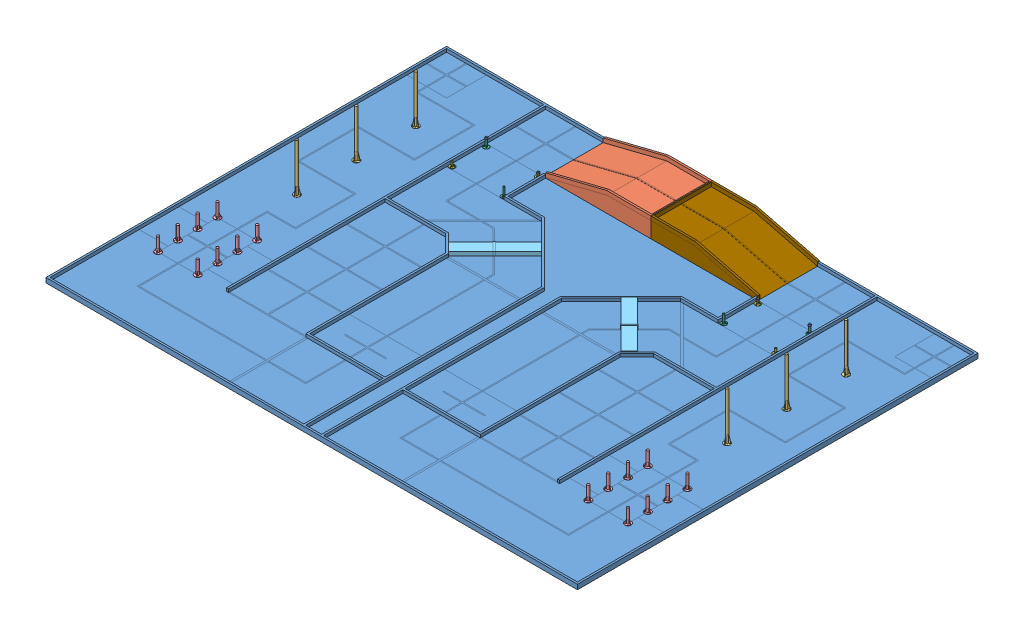
SolidWorks assembly Arena assmebly, configuration Default. Lengths in mm.
Overall size (13400 1240 10100).
39 component instances, 9 part files, 54 mates.
Components (placement in the parent):
- Layout-1: Layout [Default] at (7939.3308 4716.4188 7585.328) size (13400 120 10100)
- mountain-1: mountain [Default] at (7604.3187 4736.4188 3571.4942) size (2700.73 500 1550)
- forest tree-1: forest tree [Default] at (2179.3187 4741.4188 4846.4942) x (-0.822314 0 0.569035) z (-0.569035 0 -0.822314) size (160 1200 160)
- forest tree-2: forest tree [Default] at (2179.3187 4741.4188 6346.4942) size (160 1200 160)
- forest tree-3: forest tree [Default] at (2179.3187 4741.4188 7846.4942) size (160 1200 160)
- bridge-1: bridge [Default] at (1679.3187 4741.4188 9346.4942) size (160 350 160)
- bridge-2: bridge [Default] at (1679.3187 4741.4188 10846.4942) size (160 350 160)
- bridge-3: bridge [Default] at (1679.3187 4741.4188 10346.4942) size (160 350 160)
- bridge-4: bridge [Default] at (1679.3187 4741.4188 9846.4942) size (160 350 160)
- bridge-5: bridge [Default] at (2679.3187 4741.4188 9846.4942) size (160 350 160)
- bridge-6: bridge [Default] at (2679.3187 4741.4188 10846.4942) size (160 350 160)
- bridge-7: bridge [Default] at (2679.3187 4741.4188 10346.4942) size (160 350 160)
- bridge-8: bridge [Default] at (2679.3187 4741.4188 9346.4942) size (160 350 160)
- sand dune-1: sand dune [Default] at (5914.6178 4786.4188 6581.2976) x (0.707107 0 -0.707107) z (0.707107 0 0.707107) size (1661 103 306)
- big tussock-1: big tussock [Default] at (3524.3187 4741.4188 4416.4942) x (0.505909 0 -0.862587) z (0.862587 0 0.505909) size (140 220 140)
- big tussock-2: big tussock [Default] at (4834.3187 4741.4188 5276.4942) size (140 220 140)
- small tussock-1: small tussock [Default] at (4834.3187 4741.4188 4416.4942) size (140 120 140)
- small tussock-2: small tussock [Default] at (3524.3187 4741.4188 5276.4942) size (140 120 140)
- rope-2: rope [Default] at (4837.6429 4808.0977 4416.2239) x (0.973213 0.084542 0.213798) z (-0.212051 -0.029236 0.976821) size (71.08 49.96 70.15)
- rope-3: rope [Default] at (3527.7017 4909.2003 4416.5029) x (0.996381 0.084578 0.008439) z (-0.008428 -0.000496 0.999964) size (71.08 49.96 70.15)
- forest tree-7: forest tree [Default] at (13029.3187 4741.4188 4846.4942) x (-0.822314 0 -0.569035) z (0.569035 0 -0.822314) size (160 1200 160)
- forest tree-8: forest tree [Default] at (13029.3187 4741.4188 6346.4942) size (160 1200 160)
- forest tree-9: forest tree [Default] at (13029.3187 4741.4188 7846.4942) size (160 1200 160)
- sand dune-3: sand dune [Default] at (9294.0196 4786.4188 6581.2976) x (-0.707107 0 -0.707107) z (0.707107 0 -0.707107) size (1661 103 306)
- bridge-17: bridge [Default] at (12529.3187 4741.4188 10846.4942) x (-1 0 0) z (0 0 -1) size (160 350 160)
- bridge-18: bridge [Default] at (12529.3187 4741.4188 10346.4942) x (-1 0 0) z (0 0 -1) size (160 350 160)
- bridge-19: bridge [Default] at (12529.3187 4741.4188 9846.4942) x (-1 0 0) z (0 0 -1) size (160 350 160)
- bridge-20: bridge [Default] at (12529.3187 4741.4188 9346.4942) x (-1 0 0) z (0 0 -1) size (160 350 160)
- bridge-21: bridge [Default] at (13529.3187 4741.4188 9346.4942) x (-1 0 0) z (0 0 -1) size (160 350 160)
- bridge-22: bridge [Default] at (13529.3187 4741.4188 9846.4942) x (-1 0 0) z (0 0 -1) size (160 350 160)
- bridge-23: bridge [Default] at (13529.3187 4741.4188 10346.4942) x (-1 0 0) z (0 0 -1) size (160 350 160)
- bridge-24: bridge [Default] at (13529.3187 4741.4188 10846.4942) x (-1 0 0) z (0 0 -1) size (160 350 160)
- small tussock-5: small tussock [Default] at (11684.3187 4741.4188 5276.4942) size (140 120 140)
- rope-6: rope [Default] at (11680.9357 4909.2003 4416.5029) x (0.996381 -0.084578 -0.008439) z (0.008428 -0.000496 0.999964) size (71.08 49.96 70.15)
- small tussock-6: small tussock [Default] at (10374.3187 4741.4188 4416.4942) size (140 120 140)
- big tussock-5: big tussock [Default] at (10374.3187 4741.4188 5276.4942) size (140 220 140)
- big tussock-6: big tussock [Default] at (11684.3187 4741.4188 4416.4942) x (0.505909 0 0.862587) z (-0.862587 0 0.505909) size (140 220 140)
- rope-7: rope [Default] at (10370.9945 4808.0977 4416.2239) x (0.973213 -0.084542 -0.213798) z (0.212051 -0.029236 0.976821) size (71.08 49.96 70.15)
- mountain_blueside-1: mountain_blueside [Default] at (7604.3187 4736.4188 3571.4942) x (-1 0 0) z (0 0 -1) size (2700.73 500 1550)
Mates (geometry in assembly coordinates):
- Coincident3: coincident anti-aligned: plane of Layout-1 through (7939.3308 4736.4188 7585.328) normal (0 1 0); plane of mountain-1 through (4904.3187 4736.4188 2796.4942) normal (0 -1 0)
- Coincident6: coincident aligned: plane of Layout-1 through (7939.3308 4696.4188 2796.4942) normal (0 0 -1); plane of mountain-1 through (7604.3187 4736.4188 2796.4942) normal (0 0 -1)
- Coincident8: coincident anti-aligned: line of Layout-1 through (4904.3187 4736.4188 4346.4942) axis (0 0 -1); line of mountain-1 through (4904.3187 4736.4188 2796.4942) axis (0 0 1)
- Coincident9: coincident aligned: plane of Layout-1 through (7939.3308 4736.4188 7585.328) normal (0 1 0); circle of forest tree-1
- Distance1: distance = 1225 mm: cylinder of forest tree-1 through (2179.3187 4936.4188 4846.4942) axis (0 -1 0) radius 30; plane of Layout-1 through (954.3187 4696.4188 7585.328) normal (1 0 0)
- Distance2: distance = 2000 mm: cylinder of forest tree-1 through (2179.3187 4936.4188 4846.4942) axis (0 -1 0) radius 30; plane of Layout-1 through (7939.3308 4696.4188 2846.4942) normal (0 0 1)
- Coincident10: coincident anti-aligned: plane of Layout-1 through (7939.3308 4736.4188 7585.328) normal (0 1 0); plane of forest tree-2 through (2179.3187 4736.4188 6346.4942) normal (0 -1 0)
- Distance3: distance = 1225 mm: cylinder of forest tree-2 through (2179.3187 4936.4188 6346.4942) axis (0 -1 0) radius 30; plane of Layout-1 through (954.3187 4696.4188 7585.328) normal (1 0 0)
- Distance4: distance = 1500 mm: cylinder of forest tree-2 through (2179.3187 4936.4188 6346.4942) axis (0 -1 0) radius 30; cylinder of forest tree-1 through (2179.3187 4936.4188 4846.4942) axis (0 -1 0) radius 30
- Coincident11: coincident anti-aligned: plane of Layout-1 through (7939.3308 4736.4188 7585.328) normal (0 1 0); plane of forest tree-3 through (2179.3187 4736.4188 7846.4942) normal (0 -1 0)
- Distance5: distance = 1500 mm: cylinder of forest tree-3 through (2179.3187 4936.4188 7846.4942) axis (0 -1 0) radius 30; cylinder of forest tree-2 through (2179.3187 4936.4188 6346.4942) axis (0 -1 0) radius 30
- Distance6: distance = 1225 mm: cylinder of forest tree-3 through (2179.3187 4936.4188 7846.4942) axis (0 -1 0) radius 30; plane of Layout-1 through (954.3187 4696.4188 7585.328) normal (1 0 0)
- Coincident12: coincident anti-aligned: plane of Layout-1 through (7939.3308 4736.4188 7585.328) normal (0 1 0); plane of bridge-1 through (1679.3187 4736.4188 9346.4942) normal (0 -1 0)
- Concentric2: concentric: point of Layout-1; cylinder of bridge-1 through (1679.3187 5086.4188 9346.4942) axis (0 -1 0) radius 30
- Coincident15: coincident anti-aligned: plane of Layout-1 through (7939.3308 4736.4188 7585.328) normal (0 1 0); plane of bridge-2 through (1679.3187 4736.4188 10846.4942) normal (0 -1 0)
- Concentric3: concentric: point of Layout-1; cylinder of bridge-2 through (1679.3187 5086.4188 10846.4942) axis (0 -1 0) radius 30
- Coincident17: coincident anti-aligned: plane of Layout-1 through (7939.3308 4736.4188 7585.328) normal (0 1 0); plane of bridge-3 through (1679.3187 4736.4188 10346.4942) normal (0 -1 0)
- Distance8: distance = 500 mm: cylinder of bridge-3 through (1679.3187 5086.4188 10346.4942) axis (0 -1 0) radius 30; cylinder of bridge-2 through (1679.3187 5086.4188 10846.4942) axis (0 -1 0) radius 30
- Distance9: distance = 725 mm: cylinder of bridge-3 through (1679.3187 5086.4188 10346.4942) axis (0 -1 0) radius 30; plane of Layout-1 through (954.3187 4696.4188 7585.328) normal (1 0 0)
- Coincident18: coincident anti-aligned: plane of Layout-1 through (7939.3308 4736.4188 7585.328) normal (0 1 0); plane of bridge-4 through (1679.3187 4736.4188 9846.4942) normal (0 -1 0)
- Distance10: distance = 725 mm: cylinder of bridge-4 through (1679.3187 5086.4188 9846.4942) axis (0 -1 0) radius 30; plane of Layout-1 through (954.3187 4696.4188 7585.328) normal (1 0 0)
- Distance11: distance = 500 mm: cylinder of bridge-4 through (1679.3187 5086.4188 9846.4942) axis (0 -1 0) radius 30; cylinder of bridge-3 through (1679.3187 5086.4188 10346.4942) axis (0 -1 0) radius 30
- Coincident19: coincident anti-aligned: plane of Layout-1 through (7939.3308 4736.4188 7585.328) normal (0 1 0); plane of bridge-8 through (2679.3187 4736.4188 9346.4942) normal (0 -1 0)
- Concentric6: concentric: point of Layout-1; cylinder of bridge-8 through (2679.3187 5086.4188 9346.4942) axis (0 -1 0) radius 30
- Coincident21: coincident anti-aligned: plane of Layout-1 through (7939.3308 4736.4188 7585.328) normal (0 1 0); plane of bridge-6 through (2679.3187 4736.4188 10846.4942) normal (0 -1 0)
- Concentric7: concentric: point of Layout-1; cylinder of bridge-6 through (2679.3187 5086.4188 10846.4942) axis (0 -1 0) radius 30
- Coincident23: coincident anti-aligned: plane of Layout-1 through (7939.3308 4736.4188 7585.328) normal (0 1 0); plane of bridge-7 through (2679.3187 4736.4188 10346.4942) normal (0 -1 0)
- Distance12: distance = 500 mm: cylinder of bridge-7 through (2679.3187 5086.4188 10346.4942) axis (0 -1 0) radius 30; cylinder of bridge-6 through (2679.3187 5086.4188 10846.4942) axis (0 -1 0) radius 30
- Distance13: distance = 725 mm: cylinder of bridge-7 through (2679.3187 5086.4188 10346.4942) axis (0 -1 0) radius 30; plane of Layout-1 through (3404.3187 4696.4188 2846.4942) normal (-1 0 0)
- Coincident24: coincident anti-aligned: plane of Layout-1 through (7939.3308 4736.4188 7585.328) normal (0 1 0); plane of bridge-5 through (2679.3187 4736.4188 9846.4942) normal (0 -1 0)
- Distance15: distance = 500 mm: cylinder of bridge-5 through (2679.3187 5086.4188 9846.4942) axis (0 -1 0) radius 30; cylinder of bridge-8 through (2679.3187 5086.4188 9346.4942) axis (0 -1 0) radius 30
- Distance16: distance = 725 mm: cylinder of bridge-5 through (2679.3187 5086.4188 9846.4942) axis (0 -1 0) radius 30; plane of Layout-1 through (3404.3187 4696.4188 2846.4942) normal (-1 0 0)
- Coincident25: coincident anti-aligned: plane of Layout-1 through (7939.3308 4736.4188 7585.328) normal (0 1 0); plane of sand dune-1 through (5221.2996 4736.4188 7062.4838) normal (0 -1 0)
- Parallel4: parallel anti-aligned: plane of Layout-1 through (5004.3187 4696.4188 6846.4942) normal (0.707107 0 -0.707107); plane of sand dune-1 through (5221.2996 4736.4188 7062.4838) normal (-0.707107 0 0.707107)
- Coincident36: coincident anti-aligned: plane of Layout-1 through (7939.3308 4736.4188 7585.328) normal (0 1 0); plane of big tussock-1 through (3524.3187 4736.4188 4416.4942) normal (0 -1 0)
- Tangent1: tangent: plane of Layout-1 through (3454.3187 4696.4188 2846.4942) normal (1 0 0); circle of big tussock-1
- Tangent2: tangent: line of Layout-1 through (3454.3187 4736.4188 4346.4942) axis (1 0 0); cylinder of big tussock-1 through (3524.3187 4736.4188 4416.4942) axis (0 1 0) radius 70
- Coincident39: coincident anti-aligned: plane of Layout-1 through (7939.3308 4736.4188 7585.328) normal (0 1 0); plane of big tussock-2 through (4834.3187 4736.4188 5276.4942) normal (0 -1 0)
- Tangent3: tangent: plane of Layout-1 through (4904.3187 4696.4188 7585.328) normal (-1 0 0); circle of big tussock-2
- Tangent4: tangent: line of Layout-1 through (5783.6081 4736.4188 5346.4942) axis (-1 0 0); cylinder of big tussock-2 through (4834.3187 4736.4188 5276.4942) axis (0 1 0) radius 70
- Coincident42: coincident anti-aligned: plane of Layout-1 through (7939.3308 4736.4188 7585.328) normal (0 1 0); plane of small tussock-1 through (4834.3187 4736.4188 4416.4942) normal (0 -1 0)
- Tangent5: tangent: plane of Layout-1 through (4904.3187 4696.4188 7585.328) normal (-1 0 0); circle of small tussock-1
- Tangent6: tangent: line of Layout-1 through (4218.9852 4736.4188 4346.4942) axis (1 0 0); cylinder of small tussock-1 through (4834.3187 4736.4188 4416.4942) axis (0 1 0) radius 70
- Coincident45: coincident anti-aligned: plane of Layout-1 through (7939.3308 4736.4188 7585.328) normal (0 1 0); plane of small tussock-2 through (3524.3187 4736.4188 5276.4942) normal (0 -1 0)
- Tangent7: tangent anti-aligned: plane of Layout-1 through (3454.3187 4696.4188 2846.4942) normal (1 0 0); cylinder of small tussock-2 through (3524.3187 4736.4188 5276.4942) axis (0 1 0) radius 70
- Tangent8: tangent: line of Layout-1 through (3454.3187 4736.4188 5346.4942) axis (1 0 0); cylinder of small tussock-2 through (3524.3187 4736.4188 5276.4942) axis (0 1 0) radius 70
- Tangent11: tangent anti-aligned: cylinder of small tussock-1 through (4834.3187 4856.4188 4416.4942) axis (0 -1 0) radius 20; face of ?
- Perpendicular3: perpendicular: plane of small tussock-1 through (4834.3187 4856.4188 4416.4942) normal (0 1 0); plane of rope-2 through (4828.7573 4852.2043 4441.2083) normal (-0.977239 0 -0.212141)
- Tangent12: tangent anti-aligned: cylinder of big tussock-1 through (3524.3187 4956.4188 4416.4942) axis (0 -1 0) radius 20; edge_curve of rope-3
- Perpendicular4: perpendicular: plane of big tussock-1 through (3524.3187 4956.4188 4416.4942) normal (0 1 0); plane of rope-3 through (3524.1078 4954.0446 4441.4957) normal (-0.999964 0 -0.008428)
- Coincident46: coincident anti-aligned: plane of Layout-1 through (8016.2417 4696.4188 7508.4171) normal (-0.707107 0 0.707107); plane of sand dune-1 through (6395.804 4736.4188 5887.9794) normal (0.707107 0 -0.707107)
- Coincident50: coincident anti-aligned: plane of mountain-1 through (7604.3187 4736.4188 2796.4942) normal (1 0 0); plane of mountain_blueside-1 through (7604.3187 4736.4188 4346.4942) normal (-1 0 0)
- Coincident51: coincident aligned: plane of mountain-1 through (7604.3187 4736.4188 4346.4942) normal (0 0 1); plane of mountain_blueside-1 through (7604.3187 4736.4188 4346.4942) normal (0 0 1)
- Coincident52: coincident anti-aligned: plane of Layout-1 through (7269.3067 4736.4188 7585.328) normal (0 1 0); plane of mountain_blueside-1 through (10304.3187 4736.4188 4346.4942) normal (0 -1 0)
